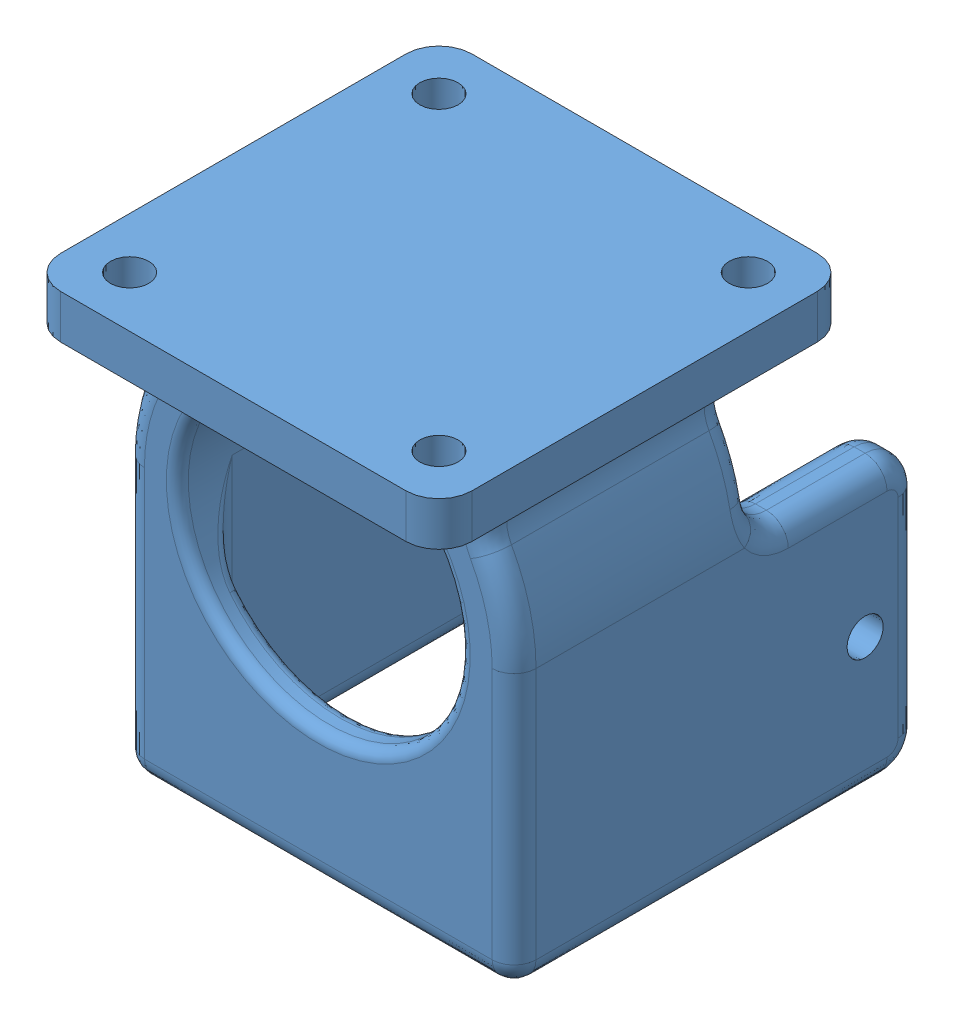
SolidWorks assembly Lidar_mount, configuration 默认. Lengths in mm.
Overall size (37.5 42.85 44.75).
2 component instances, 2 part files, 2 mates.
Components (placement in the parent):
- Lidar_mount-1: Lidar_mount [默认] at origin size (37.5 42.85 44.75)
- stand-1: stand [默认] at (0.1 -28.85 -21) size (25.5 5 5)
Mates (geometry in assembly coordinates):
- Concentric3: concentric: cylinder of Lidar_mount-1 through (-18.75 -26.35 -21) axis (1 0 0) radius 1.65; cylinder of stand-1 through (-12.65 -26.35 -21) axis (1 0 0) radius 1.65
- Coincident4: coincident anti-aligned: plane of Lidar_mount-1 through (12.85 0 11) normal (-1 0 0); plane of stand-1 through (12.85 -23.85 -18.5) normal (1 0 0)
